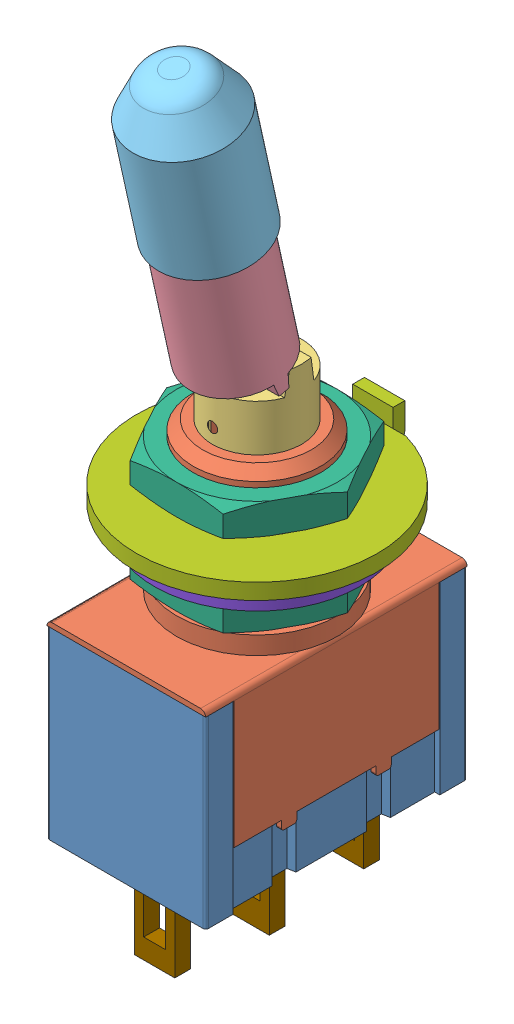
SolidWorks assembly M2012LL1W01, configuration Default. Lengths in mm.
Overall size (11.99 38.89 13).
10 component instances, 9 part files, 0 mates.
Components (placement in the parent):
- _M20123LL1W01-switch-1: _M20123LL1W01-switch [Default] at origin size (7.9 9.17 13)
- _M201L1M201-bushing-1: _M201L1M201-bushing [Default] at (0 -0.254 0) size (8 14.44 13)
- _M20L1M20L12-contact-1: _M20L1M20L12-contact [Default] x (0 0 -1) z (1 0 0) size (4.45 10.85 4.45)
- _M20L-toggles-1: _M20L-toggles [Default] at (0 9.7028 0) x (0 0 -1) z (1 0 0) size (5.81 11.6 4.6)
- _M20L-caps-1: _M20L-caps [Default] at (0 9.7028 0) x (0 0 -1) z (1 0 0) size (6.25 8.52 5.11)
- _AT513H-1: _AT513H [Default] at (0 5.9004 0) x (1 0 0) z (0 -1 0) size (8.99 8 1.5)
- _AT507H-1: _AT507H [Default] at (0 3.7871 0) x (0 0 1) z (0 1 0) size (12.34 11.99 1.7)
- _AT509-1: _AT509 [Default] at (0 2.9566 0) x (1 0 0) z (0 -1 0) size (10.21 10.21 0.51)
- _AT513H-2: _AT513H [Default] at (0 1.8352 0) x (1 0 0) z (0 -1 0) size (8.99 8 1.5)
- _M201201-terminals-1: _M201201-terminals [Default] at (0 -9.4234 0) size (6.38 5 12.5)
